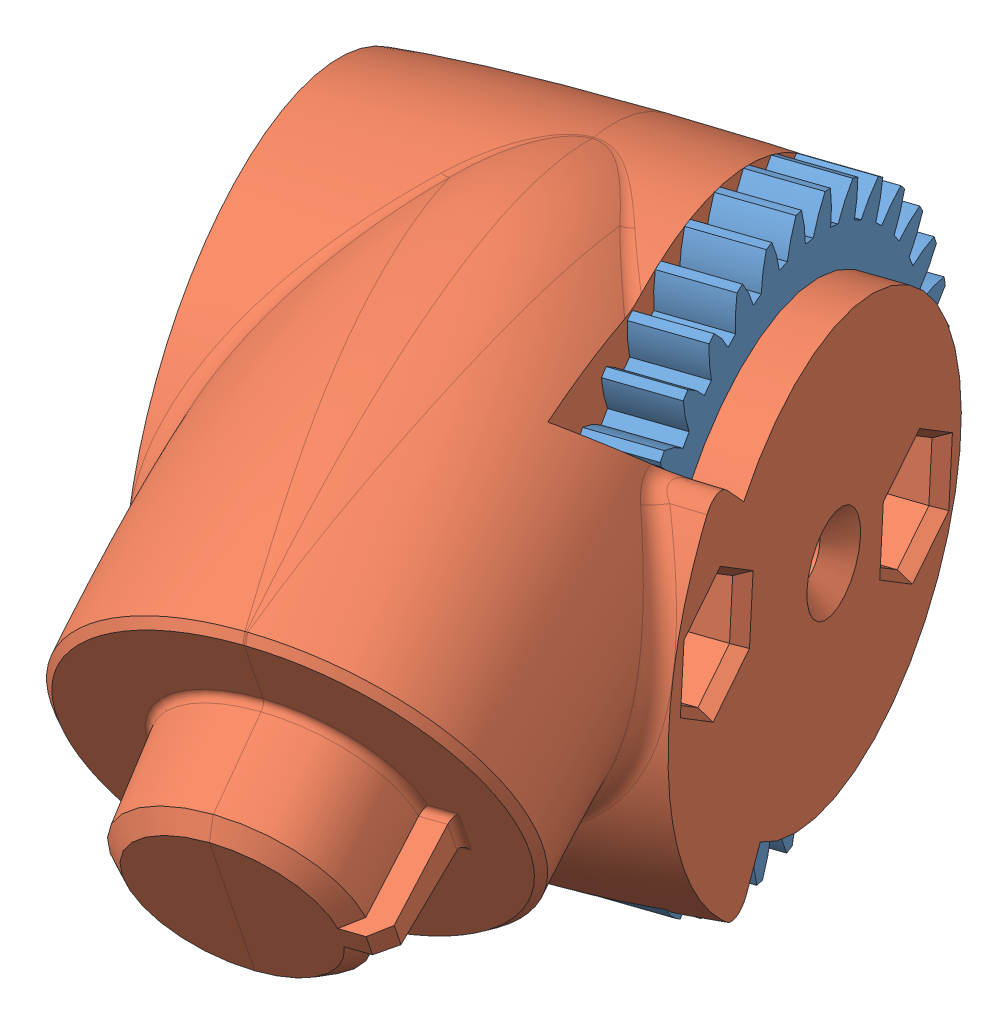
SolidWorks assembly base_beta, configuration Domyślna. Lengths in mm.
Overall size (105.45 133.11 151.24).
12 component instances, 9 part files, 32 mates.
Components (placement in the parent):
- Support-1: Support [Domyślna] x (-1 0 0) z (0 1 0) size (209.5 209.5 74.16) (hidden)
- Ring_segmented-1: Ring_segmented [Domyślna] at (-3.9829 -2 1.0093) x (0 0 1) z (-1 0 0) size (79.32 14.71 79.31) (hidden)
- Ring_segmented-3: Ring_segmented [Domyślna] at (-3.9829 -2 1.0093) size (79.32 14.71 79.31) (hidden)
- Ring_segmented-4: Ring_segmented [Domyślna] at (-3.9829 -2 1.0093) x (0 0 -1) z (1 0 0) size (79.32 14.71 79.31) (hidden)
- Ring_segmented-5: Ring_segmented [Domyślna] at (-3.9829 -2 1.0093) x (-1 0 0) z (0 0 -1) size (79.32 14.71 79.31) (hidden)
- Base_solid-1: Base_solid [Domyślna] at (-3.9829 0.5 1.0093) x (-0.946857 0 0.321655) z (-0.321655 0 -0.946857) size (145 171 145) (hidden)
- arm1_beta-1: arm1_beta [Domyślna] at (-3.9829 127.5 1.0093) x (0.946857 0 -0.321655) z (0.125738 0.920429 0.370135) size (96.1 85.14 240.11) (hidden)
- Gear ISO - Spur gear 2M 50T 20PA 9FW ---S50A75H50L70.0N_beta-1: Gear ISO - Spur gear 2M 50T 20PA 9FW ---S50A75H50L70.0N_beta [ISO - Spur gear 2M 50T 20PA 9FW ---S50A75H50L70.0N] at (12.5871 127.5 -4.6197) x (0.946857 0 -0.321655) z (0.125738 0.920429 0.370135) size (9 103.84 90.05) (hidden)
- Gear ISO - Spur gear 2M 36T 20PA 9FW ---S36A75H50L56.0N_beta-1: Gear ISO - Spur gear 2M 36T 20PA 9FW ---S36A75H50L56.0N_beta [ISO - Spur gear 2M 36T 20PA 9FW ---S36A75H50L56.0N] at (30.3381 274.7687 55.4061) x (0.946857 0 -0.321655) z (0.318187 -0.146441 0.936649) size (9.08 75.81 67.35)
- arm2_new2-1: arm2_new2 [Domyślna] at (35.4001 276.7847 116.9411) x (-0.946857 0 0.321655) z (-0.291871 0.420259 -0.859182) size (69.81 72.6 160) (hidden)
- lacznik_ramienia2-1: lacznik_ramienia2 [Domyślna] at (16.1352 274.7687 60.2309) x (-0.946857 0 0.321655) z (0.291871 -0.420259 0.859182) size (64.56 97.21 106.83)
- stamp_holder-1: stamp_holder [Domyślna] at (77.5771 194.5986 241.0977) x (0.946857 0 -0.321655) z (0.152722 -0.880094 0.449568) size (68.48 66.37 134.73) (hidden)
Mates (geometry in assembly coordinates):
- Wspólnie1: coincident anti-aligned: plane of Support-1 through (-3.9829 -2 1.0093) normal (0 1 0); plane of Ring_segmented-1 through (70.0171 -2 1.0093) normal (0 -1 0)
- Koncentryczne1: concentric anti-aligned: cylinder of Support-1 through (63.0129 -19 -40.8544) axis (0 1 0) radius 1.25; cylinder of Ring_segmented-1 through (63.0129 12 -40.8544) axis (0 -1 0) radius 1.75
- Koncentryczne2: concentric anti-aligned: cylinder of Support-1 through (37.8808 -19 -65.9865) axis (0 1 0) radius 1.25; cylinder of Ring_segmented-1 through (37.8808 12 -65.9865) axis (0 -1 0) radius 1.75
- Koncentryczne3: concentric anti-aligned: cylinder of Support-1 through (-45.8465 -19 -65.9865) axis (0 1 0) radius 1.25; cylinder of Ring_segmented-3 through (-45.8465 12 -65.9865) axis (0 -1 0) radius 1.75
- Wspólnie2: coincident anti-aligned: plane of Support-1 through (-3.9829 -2 1.0093) normal (0 1 0); plane of Ring_segmented-3 through (-3.9829 -2 -72.9907) normal (0 -1 0)
- Koncentryczne4: concentric anti-aligned: cylinder of Support-1 through (-70.9787 -19 -40.8544) axis (0 1 0) radius 1.25; cylinder of Ring_segmented-3 through (-70.9787 12 -40.8544) axis (0 -1 0) radius 1.75
- Wspólnie3: coincident anti-aligned: plane of Support-1 through (-3.9829 -2 1.0093) normal (0 1 0); plane of Ring_segmented-4 through (-77.9829 -2 1.0093) normal (0 -1 0)
- Koncentryczne5: concentric anti-aligned: cylinder of Support-1 through (-70.9787 -19 42.8729) axis (0 1 0) radius 1.25; cylinder of Ring_segmented-4 through (-70.9787 12 42.8729) axis (0 -1 0) radius 1.75
- Koncentryczne6: concentric anti-aligned: cylinder of Support-1 through (-45.8465 -19 68.0051) axis (0 1 0) radius 1.25; cylinder of Ring_segmented-4 through (-45.8465 12 68.0051) axis (0 -1 0) radius 1.75
- Wspólnie4: coincident anti-aligned: plane of Support-1 through (-3.9829 -2 1.0093) normal (0 1 0); plane of Ring_segmented-5 through (-3.9829 -2 75.0093) normal (0 -1 0)
- Koncentryczne7: concentric anti-aligned: cylinder of Support-1 through (37.8808 -19 68.0051) axis (0 1 0) radius 1.25; cylinder of Ring_segmented-5 through (37.8808 12 68.0051) axis (0 -1 0) radius 1.75
- Koncentryczne8: concentric anti-aligned: cylinder of Support-1 through (63.0129 -19 42.8729) axis (0 1 0) radius 1.25; cylinder of Ring_segmented-5 through (63.0129 12 42.8729) axis (0 -1 0) radius 1.75
- Koncentryczne9: concentric anti-aligned: circle of Support-1; circle of Base_solid-1
- Wspólnie8: coincident anti-aligned: plane of Ring_segmented-1 through (63.0171 5.5 1.0093) normal (0 -1 0); plane of Base_solid-1 through (-3.9829 5.5 1.0093) normal (0 1 0)
- Wspólnie9: coincident aligned: plane of Support-1 through (0 0 0) normal (0 1 0); plane of assembly through (0 0 0) normal (0 1 0)
- Wspólnie10: coincident anti-aligned: plane of Support-1 through (0 0 0) normal (-1 0 0); plane of assembly through (0 0 0) normal (1 0 0)
- Wspólnie11: coincident aligned: plane of Support-1 through (0 0 0) normal (0 0 1); plane of assembly through (0 0 0) normal (0 0 1)
- Wspólnie12: coincident anti-aligned: plane of arm1_beta-1 through (12.5871 127.5 -4.6197) normal (0.946857 0 -0.321655); plane of Gear ISO - Spur gear 2M 50T 20PA 9FW ---S50A75H50L70.0N_beta-1 through (12.5871 127.5 -4.6197) normal (-0.946857 0 0.321655)
- Koncentryczne10: concentric anti-aligned: cylinder of arm1_beta-1 through (12.5871 127.5 -4.6197) axis (0.946857 0 -0.321655) radius 35.5; cylinder of Gear ISO - Spur gear 2M 50T 20PA 9FW ---S50A75H50L70.0N_beta-1 through (59.93 127.5 -20.7025) axis (-0.946857 0 0.321655) radius 35
- Wspólnie13: coincident anti-aligned: plane of arm1_beta-1 through (7.4774 166.8402 -19.6611) normal (-0.298257 -0.374427 -0.877979); plane of Gear ISO - Spur gear 2M 50T 20PA 9FW ---S50A75H50L70.0N_beta-1 through (21.1088 127.5 -7.5146) normal (0.298257 0.374427 0.877979)
- Koncentryczne11: concentric anti-aligned: cylinder of Base_solid-1 through (64.6652 127.5 -22.311) axis (-0.946857 0 0.321655) radius 3.5; cylinder of arm1_beta-1 through (-49.432 127.5 16.4487) axis (0.946857 0 -0.321655) radius 3.025
- Szerokość1: width aligned: plane of Base_solid-1 through (-30.0214 127.5 9.8548) normal (0.946857 0 -0.321655); plane of Base_solid-1 through (22.0557 127.5 -7.8362) normal (-0.946857 0 0.321655); plane of arm1_beta-1 through (3.3452 150.9546 -59.8055) normal (0.946857 0 -0.321655); plane of arm1_beta-1 through (-46.8382 150.9546 -42.7578) normal (-0.946857 0 0.321655)
- Koncentryczne12: concentric aligned: cylinder of arm1_beta-1 through (-29.3139 274.7687 75.6703) axis (0.946857 0 -0.321655) radius 3.025; cylinder of lacznik_ramienia2-1 through (-12.2866 274.7687 69.886) axis (0.946857 0 -0.321655) radius 3
- Koncentryczne13: concentric anti-aligned: cylinder of Gear ISO - Spur gear 2M 36T 20PA 9FW ---S36A75H50L56.0N_beta-1 through (77.6809 274.7687 39.3233) axis (-0.946857 0 0.321655) radius 28; cylinder of lacznik_ramienia2-1 through (30.3381 274.7687 55.4061) axis (0.946857 0 -0.321655) radius 28.5
- Szerokość3: width anti-aligned: plane of lacznik_ramienia2-1 through (-12.2705 274.7687 69.8805) normal (-0.946857 0 0.321655); plane of lacznik_ramienia2-1 through (44.5409 274.7687 50.5812) normal (0.946857 0 -0.321655); plane of arm1_beta-1 through (-50.1522 150.9546 -41.632) normal (0.946857 0 -0.321655); plane of arm1_beta-1 through (6.6592 150.9546 -60.9313) normal (-0.946857 0 0.321655)
- Wspólnie22: coincident anti-aligned: plane of arm2_new2-1 through (35.4001 276.7847 116.9411) normal (-0.291871 0.420259 -0.859182); plane of lacznik_ramienia2-1 through (35.4001 276.7847 116.9411) normal (0.291871 -0.420259 0.859182)
- Koncentryczne14: concentric aligned: circle of arm2_new2-1; circle of lacznik_ramienia2-1
- Równolegle3: parallel anti-aligned: plane of arm2_new2-1 through (53.1537 276.7847 110.9101) normal (-0.960835 0.021995 0.276248); plane of lacznik_ramienia2-1 through (48.7937 252.2848 100.4073) normal (0.960835 -0.021995 -0.276248)
- Koncentryczne15: concentric anti-aligned: cone of arm2_new2-1 through (83.976 223.2016 222.6269) axis (-0.946857 0 0.321655); cylinder of stamp_holder-1 through (77.8214 223.2016 224.7177) axis (0.946857 0 -0.321655) radius 3.75
- Szerokość4: width anti-aligned: plane of stamp_holder-1 through (72.1012 210.0296 273.1664) normal (0.946857 0 -0.321655); plane of stamp_holder-1 through (101.4537 210.0296 263.1951) normal (-0.946857 0 0.321655); plane of arm2_new2-1 through (21.1973 276.7847 121.7659) normal (-0.946857 0 0.321655); plane of arm2_new2-1 through (49.603 276.7847 112.1163) normal (0.946857 0 -0.321655)
- Wspólnie24: coincident anti-aligned: plane of Gear ISO - Spur gear 2M 36T 20PA 9FW ---S36A75H50L56.0N_beta-1 through (38.8598 274.7687 52.5112) normal (0.228035 -0.705265 0.671268); plane of lacznik_ramienia2-1 through (36.8033 294.9736 74.4379) normal (-0.228035 0.705265 -0.671268)
- Wspólnie25: coincident anti-aligned: plane of Gear ISO - Spur gear 2M 36T 20PA 9FW ---S36A75H50L56.0N_beta-1 through (30.3381 274.7687 55.4061) normal (-0.946857 0 0.321655); plane of lacznik_ramienia2-1 through (30.3381 274.7687 55.4061) normal (0.946857 0 -0.321655)
